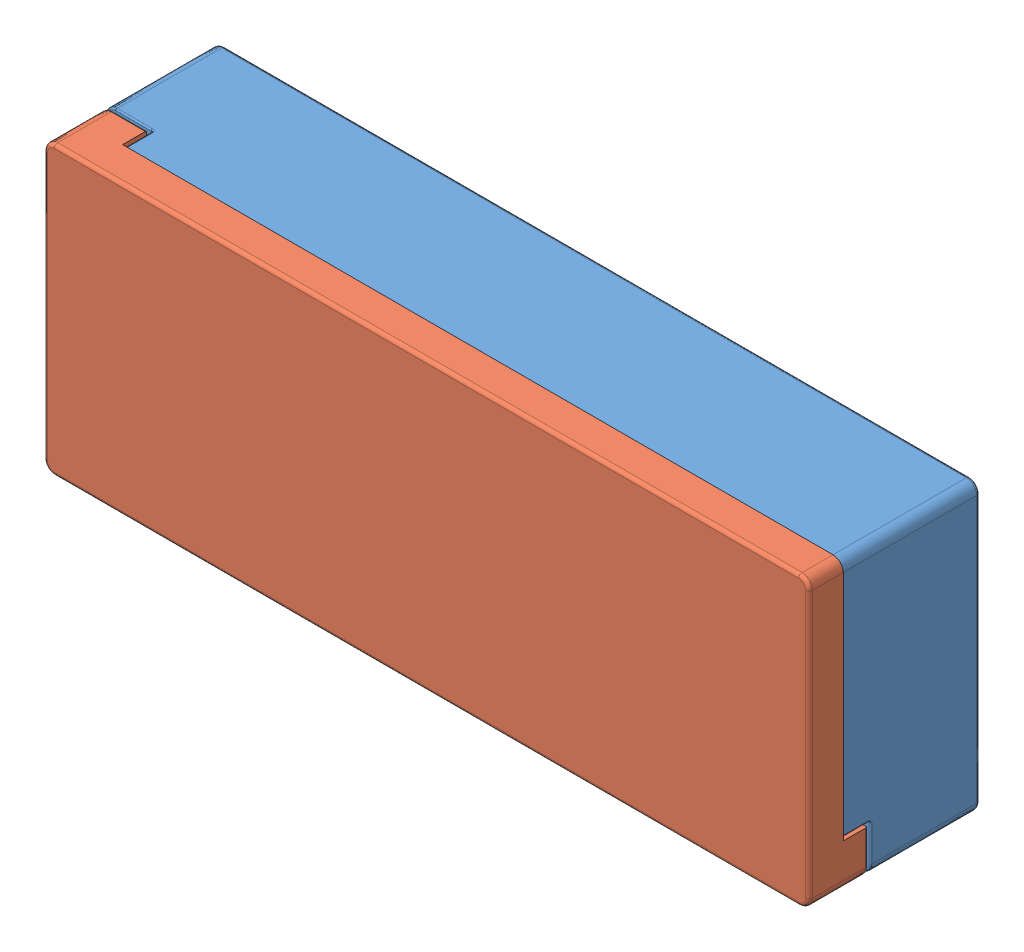
SolidWorks assembly enclosure, configuration Default. Lengths in mm.
Overall size (111.9 42 25).
2 component instances, 2 part files, 3 mates.
Components (placement in the parent):
- Bottom part-1: Bottom part [Default] at (-16.2717 79.941 76.1705) size (111.9 42 20)
- top part-1: top part [Default] at (36.6783 61.941 96.1705) size (111.9 42 12)
Mates (geometry in assembly coordinates):
- Coincident1: coincident: plane of Bottom part-1 through (-16.2717 79.941 96.1705) normal (0 0 1); plane of top part-1 through (36.6783 61.941 96.1705) normal (0 0 -1)
- Coincident2: coincident: plane of Bottom part-1 through (92.6283 82.941 96.1705) normal (1 0 0); plane of top part-1 through (92.6283 40.941 101.1705) normal (1 0 0)
- Coincident3: coincident: plane of Bottom part-1 through (-19.2717 40.941 96.1705) normal (0 -1 0); plane of top part-1 through (92.6283 40.941 101.1705) normal (0 -1 0)
